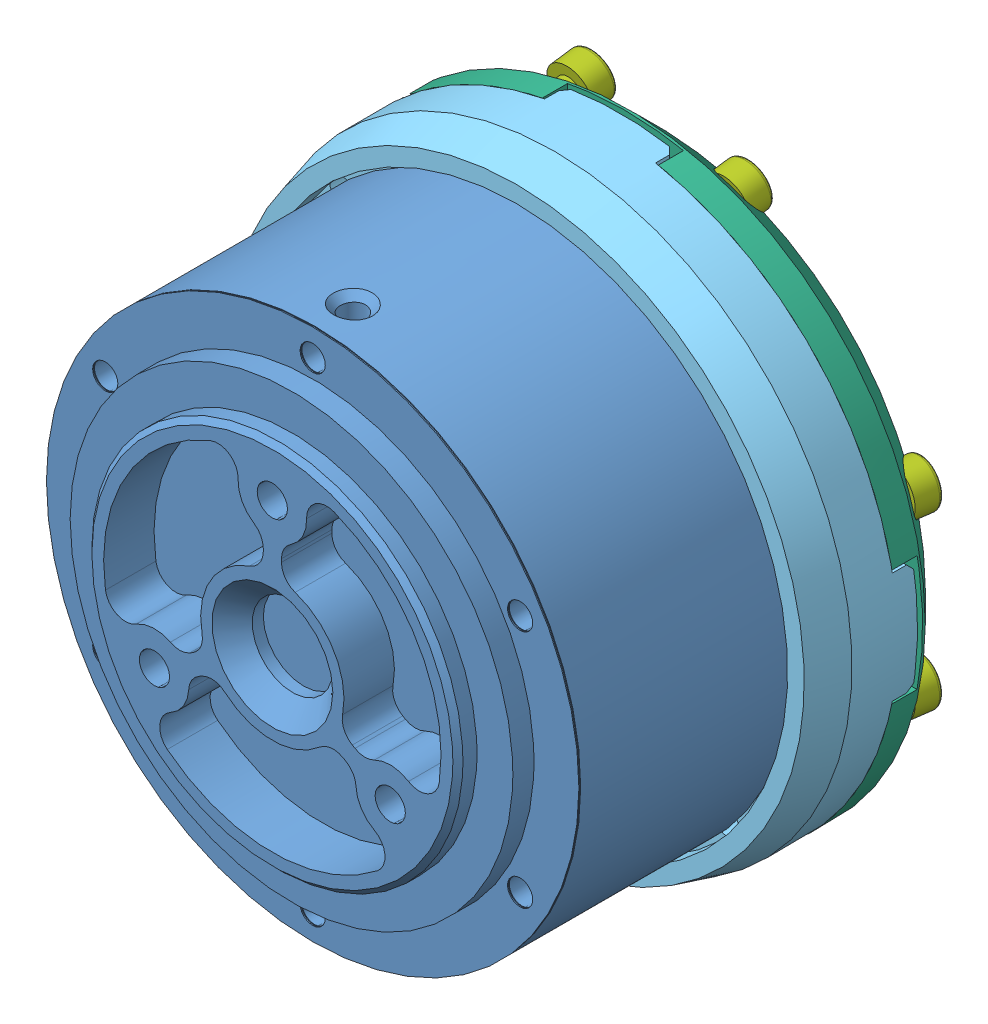
SolidWorks assembly J1 010, configuration Default. Lengths in mm.
Overall size (59.04 59.04 40.81).
15 component instances, 7 part files, 25 mates.
Components (placement in the parent):
- Servo (wo front plate) 010-1: Servo (wo front plate) 010 [Default] at (16.2104 31.3314 26.8086) size (52.8 52.8 26)
- Magnet Holder 011-1: Magnet Holder 011 [Default] at (16.2104 31.3314 33.2086) x (1 0 0) z (0 0 -1) size (8.5 8.5 8.5)
- Dagor Controller 2.5-1: Dagor Controller 2.5 [Default] at (-34.5833 -34.5928 -64.1198) size (44 44 7.5)
  - Dagor Controller Board 2.5-1: Dagor Controller Board 2.5 [Predeterminado] at (50.7937 65.9242 86.1284) size (44 44 7.5)
  - ESP32-WROOM-32U-1: ESP32-WROOM-32U [Default] at (44.7937 81.3242 85.1634) x (1 0 0) z (0 0 -1) size (18.07 19.38 3.04)
- Back Plate 100-1: Back Plate 100 [Default] at (16.2104 31.3314 28.5586) x (1 0 0) z (0 1 0) size (59 10.25 58.73)
- J2 Back Plate B 100-1: J2 Back Plate B 100 [Default] at (16.2104 31.3314 20.3086) x (-1 0.000645 0) z (0 0 -1) size (59 59 5.9)
- Screw M2.5 10mm-1: Screw M2.5 10mm [Predeterminado] at (-9.0895 39.8477 16.2913) x (-0.172113 0.984778 0.024278) z (0.139173 -0.00009 0.990268) size (4.5 4.5 12.5)
- Screw M2.5 10mm-2: Screw M2.5 10mm [Predeterminado] at (-9.1004 22.8477 16.2913) x (0.990268 0.000006 -0.139173) z (0.139173 -0.00009 0.990268) size (4.5 4.5 12.5) (hidden)
- Screw M2.5 10mm-3: Screw M2.5 10mm [Predeterminado] at (41.5103 22.815 16.2913) x (0.990268 0.000006 0.139173) z (-0.139173 0.00009 0.990268) size (4.5 4.5 12.5)
- Screw M2.5 10mm-4: Screw M2.5 10mm [Predeterminado] at (41.5212 39.815 16.2913) x (0.990268 0.000006 0.139173) z (-0.139173 0.00009 0.990268) size (4.5 4.5 12.5)
- Screw M2.5 10mm-5: Screw M2.5 10mm [Predeterminado] at (24.7267 56.6312 16.2913) x (-0.164178 0.976833 0.13727) z (-0.00009 -0.139173 0.990268) size (4.5 4.5 12.5)
- Screw M2.5 10mm-6: Screw M2.5 10mm [Predeterminado] at (7.7269 56.8468 14.8356) x (-0.164178 0.976833 0.13727) z (-0.00009 -0.139173 0.990268) size (4.5 4.5 12.5)
- Screw M2.5 10mm-7: Screw M2.5 10mm [Predeterminado] at (24.6941 6.0205 16.2913) x (0.999952 -0.00969 0.001271) z (0.00009 0.139173 0.990268) size (4.5 4.5 12.5)
- Screw M2.5 10mm-8: Screw M2.5 10mm [Predeterminado] at (7.6941 6.0315 16.2913) x (0.999952 -0.00969 0.001271) z (0.00009 0.139173 0.990268) size (4.5 4.5 12.5)
Mates (geometry in assembly coordinates):
- Concentric1: concentric anti-aligned: cylinder of Servo (wo front plate) 010-1 through (16.2104 31.3314 33.2086) axis (0 0 -1) radius 2.9; cylinder of Magnet Holder 011-1 through (16.2104 31.3314 30.2086) axis (0 0 1) radius 2.95
- Coincident1: coincident anti-aligned: plane of Servo (wo front plate) 010-1 through (16.2104 31.3314 33.2086) normal (0 0 -1); circle of Magnet Holder 011-1
- Concentric2: concentric anti-aligned: cylinder of Servo (wo front plate) 010-1 through (16.2104 31.3314 51.7086) axis (0 0 -1) radius 26.4; cylinder of Back Plate 100-1 through (16.2104 31.3314 20.3086) axis (0 0 1) radius 29.5
- Coincident2: coincident anti-aligned: plane of Servo (wo front plate) 010-1 through (16.2104 31.3314 26.8086) normal (0 0 -1); plane of Back Plate 100-1 through (16.2104 31.3314 26.8086) normal (0 0 1)
- Concentric3: concentric aligned: cylinder of Servo (wo front plate) 010-1 through (25.226 40.347 29.9086) axis (0 0 -1) radius 1.25; cylinder of Back Plate 100-1 through (25.226 40.347 28.5586) axis (0 0 -1) radius 1.4
- Coincident3: coincident anti-aligned: plane of Dagor Controller 2.5-1/Dagor Controller Board 2.5-1 through (3.7015 43.8403 22.8086) normal (0 0 1); plane of Back Plate 100-1 through (16.2104 31.3314 22.8086) normal (0 0 -1)
- Concentric7: concentric aligned: cylinder of Back Plate 100-1 through (16.2104 31.3314 20.3086) axis (0 0 1) radius 29.5; cylinder of J2 Back Plate B 100-1 through (16.2104 31.3314 14.5586) axis (0 0 1) radius 29.5
- Coincident4: coincident anti-aligned: plane of Back Plate 100-1 through (16.2104 31.3314 20.3086) normal (0 0 -1); plane of J2 Back Plate B 100-1 through (16.2104 31.3314 20.3086) normal (0 0 1)
- Concentric8: concentric anti-aligned: cylinder of J2 Back Plate B 100-1 through (-9.4265 39.8479 13.8931) axis (0.139173 -0.00009 0.990268) radius 1.35; cylinder of Screw M2.5 10mm-1 through (-7.6977 39.8468 26.194) axis (-0.139173 0.00009 -0.990268) radius 1.25
- Concentric9: concentric anti-aligned: cylinder of J2 Back Plate B 100-1 through (-9.4375 22.8479 13.8931) axis (0.139173 -0.00009 0.990268) radius 1.35; cylinder of Screw M2.5 10mm-2 through (-7.7087 22.8468 26.194) axis (-0.139173 0.00009 -0.990268) radius 1.25
- Coincident5: coincident aligned: plane of Screw M2.5 10mm-1 through (-9.4374 39.8479 13.8156) normal (-0.139173 0.00009 -0.990268); plane of Screw M2.5 10mm-2 through (-9.4484 22.8479 13.8156) normal (-0.139173 0.00009 -0.990268)
- Coincident6: coincident anti-aligned: plane of J2 Back Plate B 100-1 through (-9.1004 22.8477 16.2913) normal (-0.139173 0.00009 -0.990268); plane of Screw M2.5 10mm-2 through (-9.1004 22.8477 16.2913) normal (0.139173 -0.00009 0.990268)
- Concentric10: concentric anti-aligned: cylinder of J2 Back Plate B 100-1 through (41.8624 39.8148 13.8637) axis (-0.139173 0.00009 0.990268) radius 1.35; cylinder of Screw M2.5 10mm-4 through (40.1295 39.8159 26.194) axis (0.139173 -0.00009 -0.990268) radius 1.25
- Concentric11: concentric anti-aligned: cylinder of J2 Back Plate B 100-1 through (41.8515 22.8148 13.8637) axis (-0.139173 0.00009 0.990268) radius 1.35; cylinder of Screw M2.5 10mm-3 through (40.1185 22.8159 26.194) axis (0.139173 -0.00009 -0.990268) radius 1.25
- Coincident7: coincident aligned: plane of Screw M2.5 10mm-3 through (41.8582 22.8148 13.8156) normal (0.139173 -0.00009 -0.990268); plane of Screw M2.5 10mm-4 through (41.8692 39.8148 13.8156) normal (0.139173 -0.00009 -0.990268)
- Coincident8: coincident anti-aligned: plane of J2 Back Plate B 100-1 through (41.5103 22.815 16.2913) normal (0.139173 -0.00009 -0.990268); plane of Screw M2.5 10mm-3 through (41.5103 22.815 16.2913) normal (-0.139173 0.00009 0.990268)
- Concentric12: concentric anti-aligned: cylinder of J2 Back Plate B 100-1 through (24.7269 56.9724 13.8637) axis (-0.00009 -0.139173 0.990268) radius 1.35; cylinder of Screw M2.5 10mm-5 through (24.7258 55.2395 26.194) axis (0.00009 0.139173 -0.990268) radius 1.25
- Concentric13: concentric anti-aligned: cylinder of J2 Back Plate B 100-1 through (7.7269 56.9834 13.8637) axis (-0.00009 -0.139173 0.990268) radius 1.35; cylinder of Screw M2.5 10mm-6 through (7.726 55.4551 24.7383) axis (0.00009 0.139173 -0.990268) radius 1.25
- Coincident9: coincident anti-aligned: plane of J2 Back Plate B 100-1 through (24.7267 56.6312 16.2913) normal (0.00009 0.139173 -0.990268); plane of Screw M2.5 10mm-5 through (24.7267 56.6312 16.2913) normal (-0.00009 -0.139173 0.990268)
- Concentric14: concentric anti-aligned: cylinder of J2 Back Plate B 100-1 through (7.6939 5.6903 13.8637) axis (0.00009 0.139173 0.990268) radius 1.35; cylinder of Screw M2.5 10mm-8 through (7.695 7.4232 26.194) axis (-0.00009 -0.139173 -0.990268) radius 1.25
- Concentric15: concentric anti-aligned: cylinder of J2 Back Plate B 100-1 through (24.6939 5.6793 13.8637) axis (0.00009 0.139173 0.990268) radius 1.35; cylinder of Screw M2.5 10mm-7 through (24.695 7.4123 26.194) axis (-0.00009 -0.139173 -0.990268) radius 1.25
- Coincident10: coincident aligned: plane of Screw M2.5 10mm-7 through (24.6938 5.6726 13.8156) normal (-0.00009 -0.139173 -0.990268); plane of Screw M2.5 10mm-8 through (7.6939 5.6836 13.8156) normal (-0.00009 -0.139173 -0.990268)
- Coincident11: coincident anti-aligned: plane of J2 Back Plate B 100-1 through (24.6941 6.0205 16.2913) normal (-0.00009 -0.139173 -0.990268); plane of Screw M2.5 10mm-7 through (24.6941 6.0205 16.2913) normal (0.00009 0.139173 0.990268)
- Width1: width anti-aligned: plane of Back Plate 100-1 through (38.4604 9.0814 22.8086) normal (-1 0 0); plane of Back Plate 100-1 through (-6.0396 9.0814 22.8086) normal (1 0 0); plane of Dagor Controller 2.5-1/Dagor Controller Board 2.5-1 through (38.2104 48.3314 22.8086) normal (1 0 0); plane of Dagor Controller 2.5-1/Dagor Controller Board 2.5-1 through (-5.7896 48.3314 22.8086) normal (-1 0 0)
- Width2: width aligned: plane of Back Plate 100-1 through (-6.0396 9.0814 22.8086) normal (0 1 0); plane of Back Plate 100-1 through (-6.0396 53.5814 22.8086) normal (0 -1 0); plane of Dagor Controller 2.5-1/Dagor Controller Board 2.5-1 through (-0.7896 53.3314 22.8086) normal (0 1 0); plane of Dagor Controller 2.5-1/Dagor Controller Board 2.5-1 through (-0.7896 9.3314 22.8086) normal (0 -1 0)
